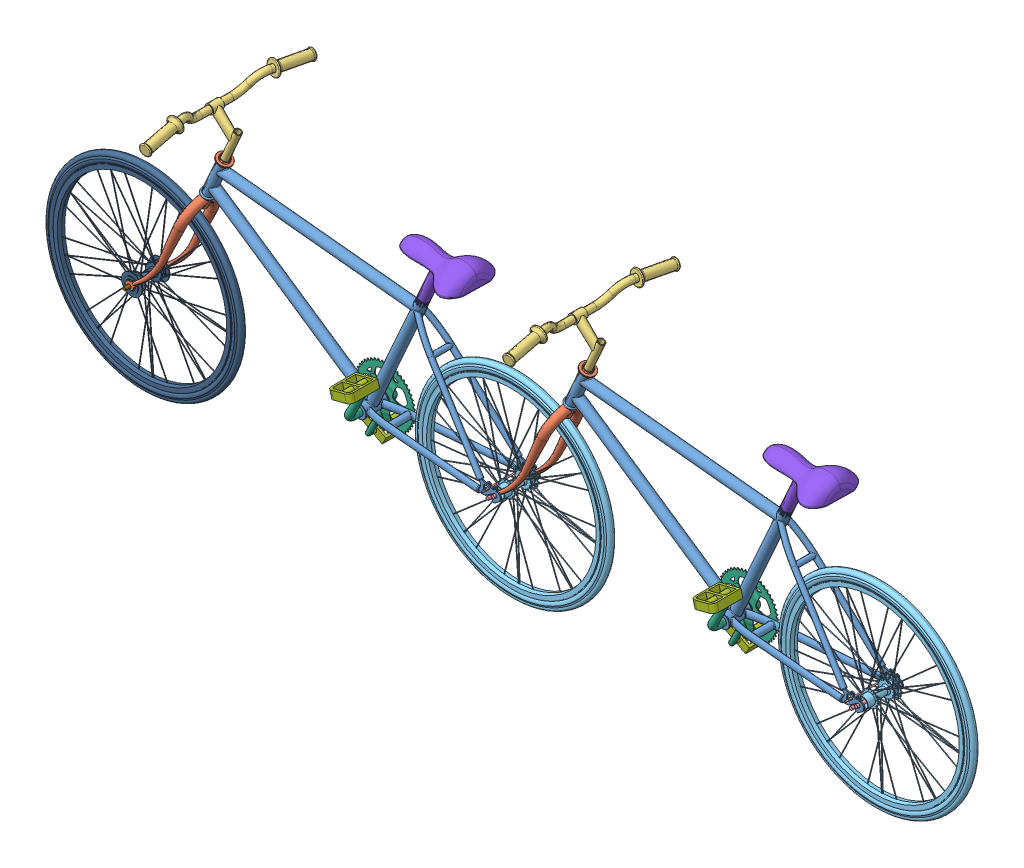
SolidWorks assembly bici_doble, configuration Predeterminado. Lengths in mm.
Overall size (3098.94 1072.61 543.01).
22 component instances, 10 part files, 2 mates.
Components (placement in the parent):
- bici _sin_lla-1: bici _sin_lla [Predeterminado] at (503.612 56.5235 610.1118) size (1631.31 1072.61 543.01)
  - cuadro-1: cuadro [Predeterminado] at (199.6567 124.6974 1021.1992) x (0 0 1) z (-1 0 0) size (139.46 474.16 1021.2)
  - soporte1-1: soporte1 [Predeterminado] at (-422.0302 -213.5231 1021.1992) x (0 0 1) z (-1 0 0) size (132.09 475.77 286.91)
  - manubrio-1: manubrio [Predeterminado] at (-393.5586 139.4524 1021.1992) x (0 0 1) z (-1 0 0) size (543.01 289.12 100.53)
  - barra_ilse-3: barra_ilse [Predeterminado] at (505.9166 -213.4411 961.0992) x (0 0 1) z (-0.8351 0.550098 0) size (140 30.58 34.04)
  - llanta_atras-2: llanta_atras [Predeterminado] at (505.9166 -213.4411 1020.1992) x (0 0 1) z (-0.845764 0.533557 0) size (98 630.55 630.55)
  - estrella-2: estrella [Predeterminado] at (45.0967 -222.4499 980.1992) x (0 0 1) z (0.883149 -0.469092 0) size (306 370 193.65)
  - pedal-1: pedal [Predeterminado] at (-37.5807 -378.105 883.0392) x (0.883149 -0.469092 0) z (0 0 -1) size (73 25 102)
  - pedal-2: pedal [Predeterminado] at (127.7742 -66.7948 1161.0392) x (0.968503 0.249002 0) z (0 0 1) size (73 25 102)
  - asiento-1: asiento [Predeterminado] at (268.6442 275.0216 1021.2274) x (0.013684 -0.006093 -0.999888) z (0.997468 -0.069714 0.014076) size (175.81 198.23 238.77)
- bici-2: bici [Predeterminado] at (-662.2393 56.5232 610.1118) size (1933.09 1072.61 543.01)
  - cuadro-1: cuadro [Predeterminado] at (199.6567 124.6974 1021.1992) x (0 0 1) z (-1 0 0) size (139.46 474.16 1021.2)
  - soporte1-1: soporte1 [Predeterminado] at (-422.0302 -213.5231 1021.1992) x (0 0 1) z (-1 0 0) size (132.09 475.77 286.91)
  - manubrio-1: manubrio [Predeterminado] at (-393.5586 139.4524 1021.1992) x (0 0 1) z (-1 0 0) size (543.01 289.12 100.53)
  - bara_delantera-1: bara_delantera [Predeterminado] at (-677.0302 -226.8231 1091.1992) x (0 0 -1) z (0 -1 0) size (140 10 10)
  - llanta_delantera-1: llanta_delantera [Predeterminado] at (-677.0302 -226.8231 1022.1992) x (0 0 -1) z (1 0 0) size (98 630.55 630.55)
  - barra_ilse-3: barra_ilse [Predeterminado] at (505.9166 -213.4411 961.0992) x (0 0 1) z (-0.8351 0.550098 0) size (140 30.58 34.04)
  - llanta_atras-2: llanta_atras [Predeterminado] at (505.9166 -213.4411 1020.1992) x (0 0 1) z (-0.845764 0.533557 0) size (98 630.55 630.55)
  - estrella-2: estrella [Predeterminado] at (45.0967 -222.4499 980.1992) x (0 0 1) z (0.883149 -0.469092 0) size (306 370 193.65)
  - pedal-1: pedal [Predeterminado] at (-37.5807 -378.105 883.0392) x (0.883149 -0.469092 0) z (0 0 -1) size (73 25 102)
  - pedal-2: pedal [Predeterminado] at (127.7742 -66.7948 1161.0392) x (0.968503 0.249002 0) z (0 0 1) size (73 25 102)
  - asiento-1: asiento [Predeterminado] at (268.6442 275.0216 1021.2274) x (0.013684 -0.006093 -0.999888) z (0.997468 -0.069714 0.014076) size (175.81 198.23 238.77)
Mates (geometry in assembly coordinates):
- Concéntrica1: concentric anti-aligned: cylinder of bici _sin_lla-1/soporte1-1 through (-173.4182 -170.2996 1685.311) axis (0 0 -1) radius 5; cylinder of bici-2/barra_ilse-3 through (-173.4182 -170.2996 1569.211) axis (0 0 1) radius 5
- Ancho1: width anti-aligned: plane of bici-2/barra_ilse-3 through (-156.3228 -156.9179 1701.311) normal (0 0 1); plane of bici-2/barra_ilse-3 through (-156.3228 -156.9179 1561.311) normal (0 0 -1); plane of bici _sin_lla-1/soporte1-1 through (-169.6644 -179.8697 1577.311) normal (0 0 -1); plane of bici _sin_lla-1/soporte1-1 through (-169.6644 -179.8697 1685.311) normal (0 0 1)
